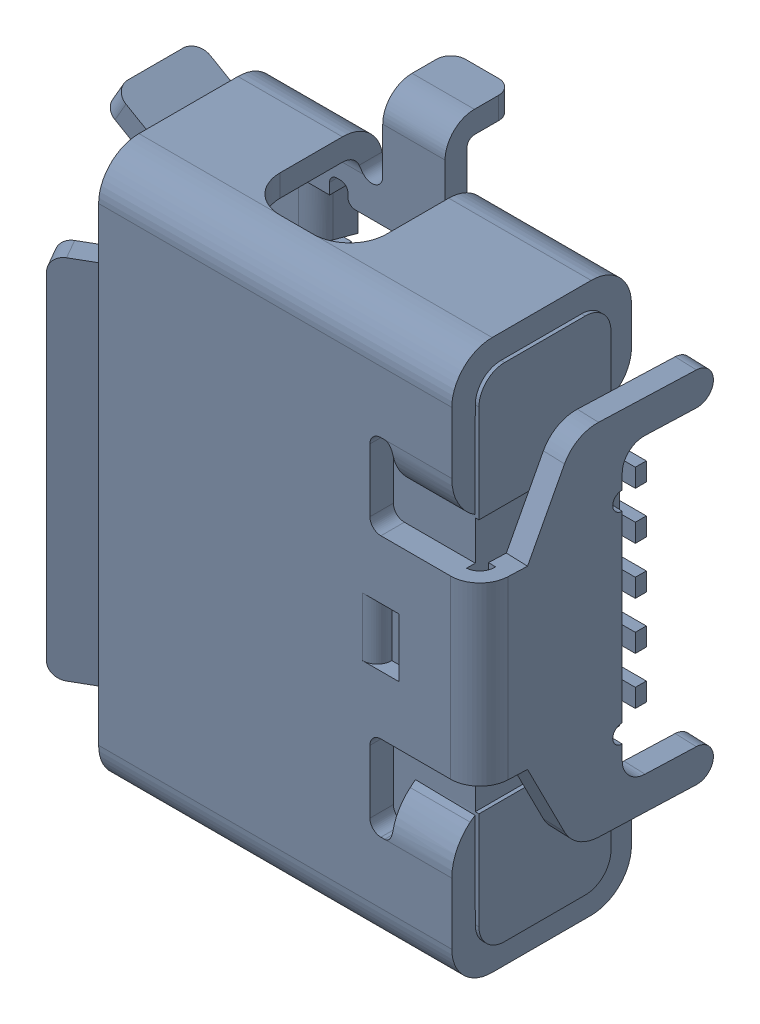
SolidWorks assembly J1, configuration Standard. Lengths in mm.
Overall size (5.9 8.66 3.36).
2 component instances, 1 part files, 0 mates.
Components (placement in the parent):
- 475900001-1: 475900001 [Standard] at (-26.2999 1.3001 0.26) x (0 1 0) z (1 0 0) size (8.66 3.36 5.9)
  - Open CASCADE STEP translator 6.8 2.177.1.1-1: Open CASCADE STEP translator 6.8 2.177.1.1 [Standard] at origin size (8.66 3.36 5.9)
